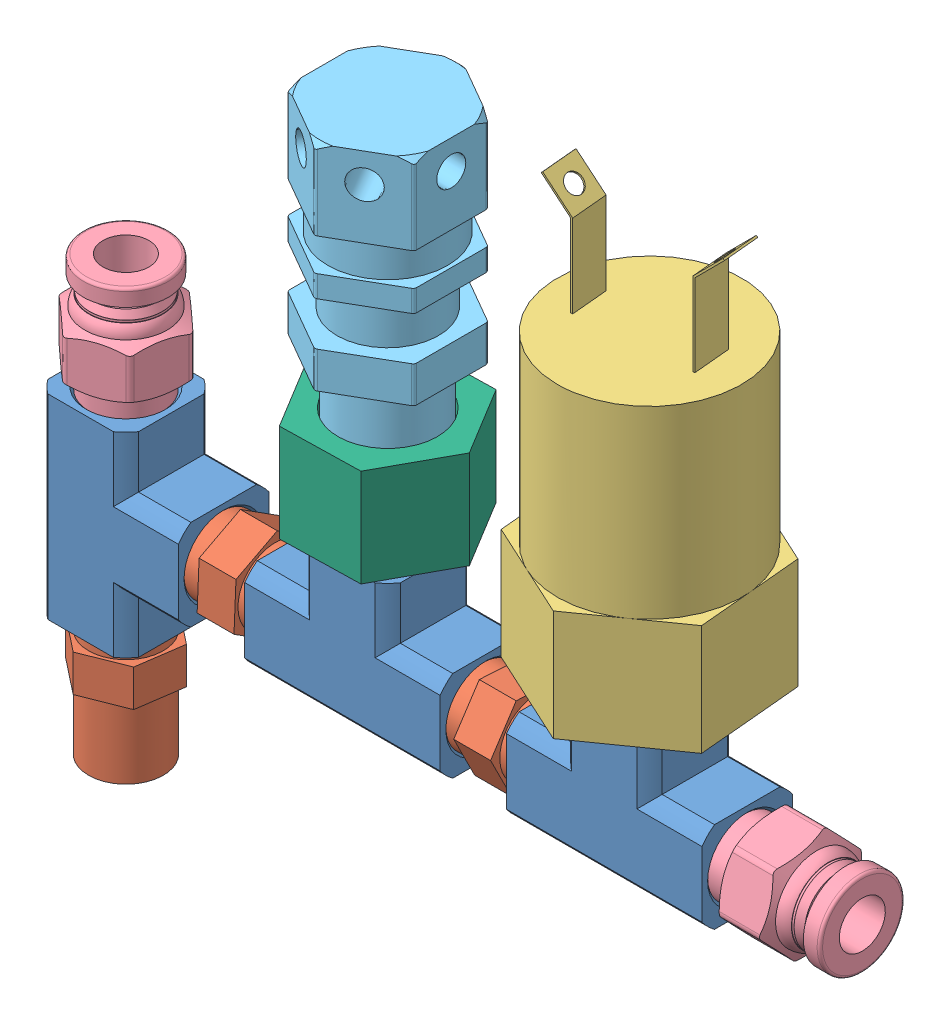
SolidWorks assembly High Pressure Block, configuration Default. Lengths in mm.
Overall size (111.06 101.73 31.53).
11 component instances, 6 part files, 25 mates.
Components (placement in the parent):
- UnionTee-1: UnionTee [Default] x (1 0 0) z (0 -1 0) size (26.92 12.5 19.71)
- HexNipple_0.125-2: HexNipple_0.125 [Default] at (-18.034 0 0) x (0 0.057278 0.998358) z (-1 0 0) size (12.83 11.11 24.64)
- PressureSwitch-1: PressureSwitch [Default] at (0 5.334 0) x (0.995826 0 -0.09127) z (0.09127 0 0.995826) size (25.4 66.04 29.33)
- PrestolokMaleConnector-1: PrestolokMaleConnector [Default] at (-72.136 6.858 0) x (0 1 0) z (0.667866 0 -0.744282) size (22.45 14.42 12.7)
- ReliefValve-1: ReliefValve [Default] at (-36.068 65.568 0) size (17.5 44 20.05)
- Adapter_0.25_0.125-1: Adapter_0.25_0.125 [Default] at (-36.068 28.956 0) x (0.999751 0 -0.022334) z (0.022334 0 0.999751) size (22 26.92 19.05)
- UnionTee-3: UnionTee [Default] at (-36.068 0 0) x (1 0 0) z (0 -1 0) size (26.92 12.5 19.71)
- UnionTee-4: UnionTee [Default] at (-72.136 0 0) x (0 -1 0) z (-1 0 0) size (26.92 12.5 19.71)
- HexNipple_0.125-3: HexNipple_0.125 [Default] at (-54.102 0 0) x (0 0.536676 0.843789) z (-1 0 0) size (12.83 11.11 24.64)
- PrestolokMaleConnector-2: PrestolokMaleConnector [Default] at (6.858 0 0) x (1 0 0) z (0 0.971535 0.236895) size (22.45 14.42 12.7)
- HexNipple_0.125-4: HexNipple_0.125 [Default] at (-72.136 -18.034 0) x (0.928821 0 -0.37053) z (0 1 0) size (12.83 11.11 24.64)
Mates (geometry in assembly coordinates):
- Coincident1: coincident anti-aligned: plane of UnionTee-1 through (0 0 0) normal (0 -1 0); plane of assembly through (0 0 0) normal (0 1 0)
- Coincident2: coincident aligned: plane of UnionTee-1 through (0 0 0) normal (0 0 1); plane of assembly through (0 0 0) normal (0 0 1)
- Coincident3: coincident aligned: plane of UnionTee-1 through (6.8732 -6.8732 0) normal (0 0 1); plane of assembly through (0 0 0) normal (1 0 0)
- Concentric4: concentric aligned: cone of UnionTee-1 through (0 12.4916 0) axis (0 -1 0); cylinder of PressureSwitch-1 through (0 15.494 0) axis (0 -1 0) radius 4.318
- Distance4: distance = 2.032 mm anti-aligned: plane of PressureSwitch-1 through (0 15.494 0) normal (0 -1 0); plane of UnionTee-1 through (0 13.462 0) normal (0 1 0)
- Concentric5: concentric aligned: cylinder of ReliefValve-1 through (-36.068 21.568 0) axis (0 1 0) radius 6.625; cylinder of Adapter_0.25_0.125-1 through (-36.068 -3.9034 0) axis (0 1 0) radius 6.858
- Distance5: distance = 7.112 mm anti-aligned: plane of Adapter_0.25_0.125-1 through (-36.068 28.956 0) normal (0 1 0); plane of ReliefValve-1 through (-44.818 36.068 -5.0518) normal (0 -1 0)
- Concentric6: concentric aligned: cone of UnionTee-1 through (-6.5447 0 0) axis (1 0 0); cylinder of HexNipple_0.125-2 through (-30.353 0 0) axis (1 0 0) radius 5.1435
- Distance6: distance = 2.032 mm anti-aligned: plane of HexNipple_0.125-2 through (-15.494 0 0) normal (1 0 0); plane of UnionTee-1 through (-13.462 0 0) normal (-1 0 0)
- Concentric7: concentric anti-aligned: cone of UnionTee-3 through (-23.5766 0 0) axis (-1 0 0); cylinder of HexNipple_0.125-2 through (-30.353 0 0) axis (1 0 0) radius 5.1435
- Distance7: distance = 2.032 mm anti-aligned: plane of UnionTee-3 through (-22.606 0 0) normal (1 0 0); plane of HexNipple_0.125-2 through (-20.574 0 0) normal (-1 0 0)
- Coincident6: coincident aligned: plane of UnionTee-1 through (0 -6.2484 -4.5106) normal (0 -1 0); plane of UnionTee-3 through (-36.068 -6.2484 -4.5106) normal (0 -1 0)
- Concentric8: concentric anti-aligned: cylinder of Adapter_0.25_0.125-1 through (-36.068 2.032 0) axis (0 1 0) radius 5.1435; cone of UnionTee-3 through (-36.068 12.4916 0) axis (0 -1 0)
- Distance8: distance = 2.032 mm: plane of UnionTee-3 through (-36.068 13.462 0) normal (0 1 0); line of Adapter_0.25_0.125-1 through (-41.7786 15.494 -9.3998) axis (-0.480533 0 0.876976)
- Concentric9: concentric aligned: cone of UnionTee-3 through (-42.6127 0 0) axis (1 0 0); cylinder of HexNipple_0.125-3 through (-66.421 0 0) axis (1 0 0) radius 5.1435
- Concentric10: concentric anti-aligned: cylinder of HexNipple_0.125-3 through (-66.421 0 0) axis (1 0 0) radius 5.1435; cone of UnionTee-4 through (-59.6444 0 0) axis (-1 0 0)
- Distance9: distance = 2.032 mm anti-aligned: plane of UnionTee-4 through (-58.674 0 0) normal (1 0 0); plane of HexNipple_0.125-3 through (-56.642 0 0) normal (-1 0 0)
- Distance10: distance = 2.032 mm anti-aligned: plane of HexNipple_0.125-3 through (-51.562 0 0) normal (1 0 0); plane of UnionTee-3 through (-49.53 0 0) normal (-1 0 0)
- Coincident8: coincident aligned: plane of UnionTee-3 through (-36.068 -6.2484 -4.5106) normal (0 -1 0); plane of UnionTee-4 through (-72.136 -6.2484 -4.5106) normal (0 -1 0)
- Concentric11: concentric aligned: cylinder of PrestolokMaleConnector-1 through (-72.136 -15.9258 0) axis (0 1 0) radius 5.0927; cone of UnionTee-4 through (-72.136 -6.5447 0) axis (0 1 0)
- Distance11: distance = 2.032 mm anti-aligned: plane of PrestolokMaleConnector-1 through (-72.136 15.494 0) normal (0 -1 0); plane of UnionTee-4 through (-72.136 13.462 0) normal (0 1 0)
- Concentric12: concentric aligned: cone of UnionTee-1 through (12.4914 0 0) axis (-1 0 0); cylinder of PrestolokMaleConnector-2 through (15.9258 0 0) axis (-1 0 0) radius 5.0927
- Distance12: distance = 2.032 mm anti-aligned: plane of UnionTee-1 through (13.462 0 0) normal (1 0 0); plane of PrestolokMaleConnector-2 through (15.494 0 0) normal (-1 0 0)
- Concentric13: concentric anti-aligned: cone of UnionTee-4 through (-72.136 12.4914 0) axis (0 -1 0); cylinder of HexNipple_0.125-4 through (-72.136 5.715 0) axis (0 1 0) radius 5.1435
- Distance13: distance = 2.032 mm anti-aligned: plane of UnionTee-4 through (-72.136 -13.462 0) normal (0 -1 0); plane of HexNipple_0.125-4 through (-72.136 -15.494 0) normal (0 1 0)
